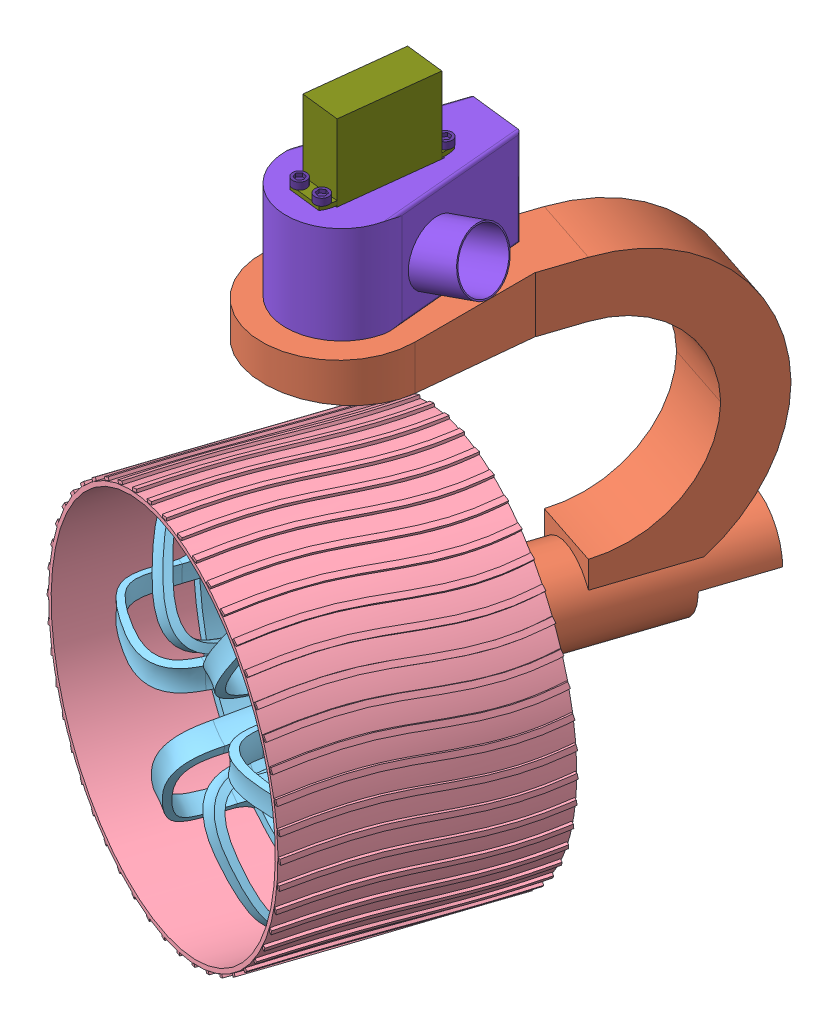
SolidWorks assembly Wheel + connector(left,front), configuration Default. Lengths in mm.
Overall size (198.17 269 202.4).
30 component instances, 17 part files, 57 mates.
Components (placement in the parent):
- Wheel motor-1: Wheel motor [Default] at (-224.1215 -139.499 45.6441) x (-0.84319 -0.459235 -0.279525) z (-0.314669 0 0.949202) size (25 25 73.38)
- Wheel connector(left,front)-1: Wheel connector(left,front) [Default] at (-218.767 -84.5922 -10.1338) x (0.314669 0 -0.949202) z (0.949202 0 0.314669) size (150.03 127 55.1)
- connector to wheel-1: connector to wheel [Default] at (-234.2078 -143.7607 83.0711) x (0.91831 0.253041 0.304428) z (0.314669 0 -0.949202) size (25 25 12.5)
- Wheel-1: Wheel [Default] at (-237.9838 -143.7607 94.4615) x (-0.819181 0.505167 -0.271566) z (-0.314669 0 0.949202) size (132 132 85)
  - Wheel Part-1-1: Wheel Part-1 [Default] at origin size (132 132 85)
  - Wheel Part-2-1: Wheel Part-2 [Default] at (0 0 -2) size (127 128.13 59.75)
- M3 nut-1: M3 nut [Default] at (-232.3491 -136.9885 71.8352) x (-0.667163 0.71132 -0.22117) z (-0.314669 0 0.949202) size (5 6.35 2.75)
- M3 nut-2: M3 nut [Default] at (-237.0959 -145.532 70.2615) x (-0.240187 0.967455 -0.079624) z (-0.314669 0 0.949202) size (5 6.35 2.75)
- M3 nut-3: M3 nut [Default] at (-224.2396 -141.9894 74.5235) x (-0.240187 0.967455 -0.079624) z (-0.314669 0 0.949202) size (5 6.35 2.75)
- M3 nut-4: M3 nut [Default] at (-228.9864 -150.5329 72.9499) x (0.251147 0.964362 0.083257) z (-0.314669 0 0.949202) size (5 6.35 2.75)
- M3 bolt for wheels-1: M3 bolt for wheels [Default] at (-244.176 -145.532 91.6186) x (-0.876804 -0.383049 -0.290668) z (0.314669 0 -0.949202) size (5 5 25.25)
- M3 bolt for wheels-2: M3 bolt for wheels [Default] at (-236.0665 -150.5329 94.3069) x (-0.876804 -0.383049 -0.290668) z (0.314669 0 -0.949202) size (5 5 25.25)
- M3 bolt for wheels-3: M3 bolt for wheels [Default] at (-231.3196 -141.9894 95.8806) x (-0.876804 -0.383049 -0.290668) z (0.314669 0 -0.949202) size (5 5 25.25)
- M3 bolt for wheels-4: M3 bolt for wheels [Default] at (-239.4291 -136.9885 93.1922) x (-0.876804 -0.383049 -0.290668) z (0.314669 0 -0.949202) size (5 5 25.25)
- Steering connector(left,front)-1: Steering connector(left,front) [Default] at (-237.0258 -27.059 85.0059) x (0.114579 0 -0.993414) z (0.993414 0 0.114579) size (70 36.07 55.83)
- Washer(M6)-1: Washer(M6) [Default] at (-237.0258 -27.559 85.0059) size (8.76 0.5 8.76)
- double row cylindrical roller bearing_is-1: double row cylindrical roller bearing_is [IS 6458 DC - 49-6-S] at (-237.0258 -22.059 85.0059) x (0.999846 0 -0.017538) z (0 -1 0) size (15 15 10)
- Steering thor joint-1: Steering thor joint [Default] at (-244.3838 -19.7982 116.189) x (0.664698 0 0.747112) z (0 1 0) size (14.13 14.13 58.56)
  - bolt head-1: bolt head [Default] at (-18.4031 26.2188 19.7392) size (14 14 8)
  - Bogie bolt-1: Bogie bolt [Default] at (-18.4064 26.2246 14.7392) x (-1 0 0) z (0 0 -1) size (9 10.39 55.56)
  - Bolt servo connector-1: Bolt servo connector [Default] at (-18.4031 26.2188 19.7392) x (0.99996 0.008969 0) z (0 0 1) size (14 14 3)
- Bogie nut-1: Bogie nut [Default] at (-237.0258 -41.6423 85.0059) x (0.979367 0 -0.20209) z (0.20209 0 0.979367) size (8.33 4.53 10.58)
- Bogie nut-2: Bogie nut [Default] at (-237.0258 -45.809 85.0059) x (0.949996 0 0.312263) z (-0.312263 0 0.949996) size (8.33 4.53 10.58)
- Servo Assembly-1: Servo Assembly [Default] at (-233.5333 1.941 85.2537) x (0.993414 0 0.114579) z (-0.114579 0 0.993414) size (14 34 44) (flexible)
  - servo shaft-1: servo shaft [Default] at (-3.4993 -1 0.1605) x (0.455252 0 0.890363) z (-0.890363 0 0.455252) size (5 18 5)
  - Servo motor-1: Servo motor [Default] at (-3.4993 3 -9.8395) size (14 30 44)
- M3 bolt-1: M3 bolt [Default] at (-242.6949 10.691 94.4349) x (0.160133 0 -0.987095) z (0 -1 0) size (5 5 12.17)
- M3 bolt-2: M3 bolt [Default] at (-229.0694 10.691 55.7212) x (-0.812704 0 -0.582677) z (0 -1 0) size (5 5 12.17)
- M3 bolt-3: M3 bolt [Default] at (-233.6548 10.691 95.4776) x (-0.635136 0 -0.772401) z (0 -1 0) size (5 5 12.17)
- M3 bolt-4: M3 bolt [Default] at (-238.1094 10.691 54.6785) x (-0.32715 0 -0.944972) z (0 -1 0) size (5 5 12.17)
Mates (geometry in assembly coordinates):
- Concentric9: concentric: cylinder of Wheel motor-1 through (-228.5514 -139.5591 59.1056) axis (0.314669 0 -0.949202) radius 12.5004; cylinder of Wheel connector(left,front)-1 through (-229.891 -139.559 63.1463) axis (0.314669 0 -0.949202) radius 12.5
- Concentric18: concentric: cylinder of Wheel motor-1 through (-234.2078 -143.7607 83.0711) axis (0.314669 0 -0.949202) radius 2.0271; cylinder of Wheel connector(left,front)-1 through (-196.7867 -143.7607 -29.8101) axis (-0.314669 0 0.949202) radius 2.435
- Concentric21: concentric: cylinder of Wheel motor-1 through (-234.2078 -143.7607 83.0711) axis (0.314669 0 -0.949202) radius 2.0271; cylinder of connector to wheel-1 through (-234.2081 -143.7607 83.072) axis (0.314669 0 -0.949202) radius 2.025
- Coincident1: coincident: axis of connector to wheel-1 through (-235.8891 -136.9885 82.5137) axis (0.314669 0 -0.949202); axis of M3 nut-1 through (-232.4874 -136.9885 72.2525) axis (-0.314669 0 0.949202)
- Coincident2: coincident: axis of connector to wheel-1 through (-240.6359 -145.532 80.9401) axis (0.314669 0 -0.949202); axis of M3 nut-2 through (-237.2343 -145.532 70.6789) axis (-0.314669 0 0.949202)
- Coincident3: coincident: axis of connector to wheel-1 through (-227.7796 -141.9894 85.202) axis (0.314669 0 -0.949202); axis of M3 nut-3 through (-224.3444 -141.9894 74.8398) axis (-0.314669 0 0.949202)
- Coincident4: coincident: axis of connector to wheel-1 through (-232.5265 -150.5329 83.6284) axis (0.314669 0 -0.949202); axis of M3 nut-4 through (-229.0913 -150.5329 73.2662) axis (-0.314669 0 0.949202)
- Coincident5: coincident: plane of connector to wheel-1 through (-231.0611 -143.7607 73.579) normal (0.314669 0 -0.949202); plane of M3 nut-1 through (-232.7424 -136.9885 73.0217) normal (-0.314669 0 0.949202)
- Parallel1: parallel: plane of connector to wheel-1 through (-233.4376 -141.2269 72.7912) normal (-0.667163 0.71132 -0.22117); plane of M3 nut-1 through (-232.049 -139.7813 73.2515) normal (0.667163 -0.71132 0.22117)
- Parallel2: parallel: plane of connector to wheel-1 through (-231.6616 -141.3421 73.38) normal (0.240187 -0.967455 0.079624); plane of M3 nut-2 through (-236.7643 -142.7481 71.6884) normal (-0.240187 0.967455 -0.079624)
- Coincident7: coincident: plane of connector to wheel-1 through (-231.0611 -143.7607 73.579) normal (0.314669 0 -0.949202); plane of M3 nut-2 through (-237.4893 -145.532 71.448) normal (-0.314669 0 0.949202)
- Coincident8: coincident: plane of connector to wheel-1 through (-228.6845 -146.2946 74.3669) normal (0.667163 -0.71132 0.22117); plane of M3 nut-4 through (-230.0731 -147.7401 73.9066) normal (-0.667163 0.71132 -0.22117)
- Coincident9: coincident: plane of connector to wheel-1 through (-231.0611 -143.7607 73.579) normal (0.314669 0 -0.949202); plane of M3 nut-4 through (-229.3798 -150.5329 74.1364) normal (-0.314669 0 0.949202)
- Parallel3: parallel: plane of connector to wheel-1 through (-225.28 -137.7426 75.4955) normal (-0.675186 -0.702868 -0.22383); plane of M3 nut-3 through (-227.2838 -142.7199 74.8312) normal (-0.675186 -0.702868 -0.22383)
- Coincident10: coincident: plane of connector to wheel-1 through (-231.0611 -143.7607 73.579) normal (0.314669 0 -0.949202); plane of M3 nut-3 through (-224.6329 -141.9894 75.71) normal (-0.314669 0 0.949202)
- Coincident11: coincident: axis of Wheel motor-1 through (-234.1652 -143.7607 82.9428) axis (0.314669 0 -0.949202); axis of Wheel-1/Wheel Part-1-1 through (-251.3572 -143.7607 134.8025) axis (0.314669 0 -0.949202)
- Coincident13: coincident: plane of connector to wheel-1 through (-234.2078 -143.7607 83.0711) normal (-0.314669 0 0.949202); plane of Wheel-1/Wheel Part-2-1 through (-234.2078 -143.7607 83.0711) normal (0.314669 0 -0.949202)
- Concentric22: concentric: cylinder of connector to wheel-1 through (-232.5268 -150.5329 83.6294) axis (0.314669 0 -0.949202) radius 1.71; cylinder of Wheel-1/Wheel Part-2-1 through (-247.7891 -150.5329 129.6685) axis (0.314669 0 -0.949202) radius 1.71
- Coincident14: coincident: axis of Wheel-1/Wheel Part-2-1 through (-243.7826 -145.532 90.4321) axis (0.314669 0 -0.949202); axis of M3 bolt for wheels-1 through (-236.7026 -145.532 69.075) axis (-0.314669 0 0.949202)
- Coincident15: coincident: plane of Wheel-1/Wheel Part-2-1 through (-243.7826 -145.532 90.4321) normal (-0.314669 0 0.949202); plane of M3 bolt for wheels-1 through (-243.7826 -145.532 90.4321) normal (0.314669 0 -0.949202)
- Coincident16: coincident: axis of Wheel-1/Wheel Part-2-1 through (-235.6731 -150.5329 93.1204) axis (0.314669 0 -0.949202); axis of M3 bolt for wheels-2 through (-228.5931 -150.5329 71.7634) axis (-0.314669 0 0.949202)
- Coincident17: coincident: plane of Wheel-1/Wheel Part-2-1 through (-237.3545 -143.7607 92.5631) normal (-0.314669 0 0.949202); plane of M3 bolt for wheels-2 through (-235.6731 -150.5329 93.1204) normal (0.314669 0 -0.949202)
- Coincident18: coincident: axis of Wheel-1/Wheel Part-2-1 through (-239.0358 -136.9885 92.0057) axis (0.314669 0 -0.949202); axis of M3 bolt for wheels-4 through (-231.9557 -136.9885 70.6487) axis (-0.314669 0 0.949202)
- Coincident19: coincident: plane of Wheel-1/Wheel Part-2-1 through (-239.0358 -136.9885 92.0057) normal (-0.314669 0 0.949202); plane of M3 bolt for wheels-4 through (-239.0358 -136.9885 92.0057) normal (0.314669 0 -0.949202)
- Coincident20: coincident: axis of Wheel-1/Wheel Part-2-1 through (-230.9263 -141.9894 94.6941) axis (0.314669 0 -0.949202); axis of M3 bolt for wheels-3 through (-223.8462 -141.9894 73.337) axis (-0.314669 0 0.949202)
- Coincident21: coincident: plane of Wheel-1/Wheel Part-2-1 through (-230.9263 -141.9894 94.6941) normal (-0.314669 0 0.949202); plane of M3 bolt for wheels-3 through (-230.9263 -141.9894 94.6941) normal (0.314669 0 -0.949202)
- Coincident22: coincident: plane of Wheel motor-1 through (-236.2696 -139.5591 82.3876) normal (-0.314669 0 0.949202); plane of connector to wheel-1 through (-234.2078 -143.7607 83.0711) normal (-0.314669 0 0.949202)
- Concentric23: concentric: cylinder of Wheel connector(left,front)-1 through (-237.0258 -51.559 85.0059) axis (0 1 0) radius 3; circle of Steering connector(left,front)-1
- Concentric24: concentric: cylinder of Steering connector(left,front)-1 through (-237.0258 -17.059 85.0059) axis (0 -1 0) radius 7.5; cylinder of double row cylindrical roller bearing_is-1 through (-237.0258 -72.4506 85.0059) axis (0 -1 0) radius 7.5
- Coincident23: coincident: plane of Steering connector(left,front)-1 through (-237.0258 -17.059 85.0059) normal (0 -1 0); plane of double row cylindrical roller bearing_is-1 through (-236.8943 -17.059 92.5047) normal (0 1 0)
- Coincident24: coincident: plane of Washer(M6)-1 through (-237.0258 -27.059 85.0059) normal (0 1 0); plane of double row cylindrical roller bearing_is-1 through (-236.9732 -27.059 88.0054) normal (0 -1 0)
- Concentric25: concentric: cylinder of Washer(M6)-1 through (-237.0258 -27.059 85.0059) axis (0 -1 0) radius 3; cylinder of double row cylindrical roller bearing_is-1 through (-237.0258 -92.9216 85.0059) axis (0 -1 0) radius 3
- Coincident25: coincident: plane of Wheel connector(left,front)-1 through (-195.0369 -27.559 -2.2671) normal (0 1 0); plane of Washer(M6)-1 through (-237.0258 -27.559 85.0059) normal (0 -1 0)
- Coincident32: coincident: plane of Steering connector(left,front)-1 through (-237.0258 -7.059 85.0059) normal (0 1 0); plane of Steering thor joint-1/bolt head-1 through (-237.0279 -7.059 85.0122) normal (0 -1 0)
- Concentric26: concentric: cylinder of Steering connector(left,front)-1 through (-237.0258 8.4751 85.0059) axis (0 -1 0) radius 3; cylinder of Steering thor joint-1/Bogie bolt-1 through (-237.0258 -55.309 85.0059) axis (0 1 0) radius 2.5
- Coincident33: coincident: plane of Wheel motor-1 through (-229.8909 -139.5591 63.1463) normal (-0.314669 0 0.949202); plane of Wheel connector(left,front)-1 through (-241.756 -84.5922 59.2129) normal (0.314669 0 -0.949202)
- Coincident83: coincident: axis of Steering thor joint-1/Bogie bolt-1 through (-237.0258 -55.309 85.0059) axis (0 1 0); axis of Bogie nut-1 through (-237.0258 -39.559 85.0059) axis (0 -1 0)
- Parallel27: parallel: plane of Wheel connector(left,front)-1 through (-236.0535 -49.559 89.7179) normal (-0.664698 0 -0.747112); plane of Bogie nut-1 through (-236.0535 -39.559 89.7179) normal (0.664698 0 0.747112)
- Coincident85: coincident: plane of Wheel connector(left,front)-1 through (-218.767 -39.559 -10.1338) normal (0 -1 0); plane of Bogie nut-1 through (-237.0258 -39.559 85.0059) normal (0 1 0)
- Coincident86: coincident: plane of Bogie nut-1 through (-237.0258 -43.7257 85.0059) normal (0 -1 0); plane of Bogie nut-2 through (-237.0258 -43.7257 85.0059) normal (0 1 0)
- Parallel29: parallel: plane of Steering thor joint-1/Bogie bolt-1 through (-240.9079 -0.059 88.4597) normal (-0.979367 0 0.20209); plane of Bogie nut-1 through (-241.5927 -39.559 83.4919) normal (-0.979367 0 0.20209)
- Lock3: lock: unknown of Bogie nut-1; unknown of Bogie nut-2
- Coincident84: coincident: axis of Steering thor joint-1/Bogie bolt-1 through (-237.0258 -55.309 85.0059) axis (0 1 0); axis of Bogie nut-2 through (-237.0258 -43.7257 85.0059) axis (0 -1 0)
- Concentric20: concentric: cylinder of Steering thor joint-1/Bolt servo connector-1 through (-237.0279 2.941 85.0122) axis (0 -1 0) radius 2.5; cylinder of Servo Assembly-1/servo shaft-1 through (-237.0279 18.941 85.0122) axis (0 -1 0) radius 2.5
- Parallel26: parallel: plane of Steering connector(left,front)-1 through (-245.3358 -7.059 91.5971) normal (0.993414 0 0.114579); plane of Servo Assembly-1/Servo motor-1 through (-242.836 34.941 74.276) normal (-0.993414 0 -0.114579)
- LimitAngle1: limit planar angle = 0.205276 rad: plane of Steering connector(left,front)-1 through (-241.231 7.941 34.1894) normal (0.114579 0 -0.993414); plane of Wheel connector(left,front)-1 through (-199.9974 -139.559 -27.0279) normal (0.314669 0 -0.949202)
- Parallel31: parallel: plane of Steering connector(left,front)-1 through (-230.4346 -7.059 93.3158) normal (-0.993414 0 -0.114579); plane of Servo Assembly-1/Servo motor-1 through (-228.9282 34.941 75.8801) normal (0.993414 0 0.114579)
- Coincident88: coincident: plane of Steering connector(left,front)-1 through (-237.0258 7.941 85.0059) normal (0 1 0); plane of Servo Assembly-1/Servo motor-1 through (-235.8821 7.941 75.0781) normal (0 -1 0)
- Coincident89: coincident: plane of Steering thor joint-1/Bolt servo connector-1 through (-237.0279 0.941 85.0122) normal (0 1 0); plane of Servo Assembly-1/servo shaft-1 through (-237.0279 0.941 85.0122) normal (0 -1 0)
- Concentric27: concentric: cylinder of Servo Assembly-1/Servo motor-1 through (-242.6949 9.441 94.4349) axis (0 -1 0) radius 1.5; cylinder of M3 bolt-1 through (-242.6949 9.441 94.4349) axis (0 1 0) radius 2.5
- Coincident90: coincident: plane of Servo Assembly-1/Servo motor-1 through (-235.8821 9.441 75.0781) normal (0 1 0); plane of M3 bolt-1 through (-242.6949 9.441 94.4349) normal (0 -1 0)
- Concentric30: concentric: cylinder of Servo Assembly-1/Servo motor-1 through (-233.6548 9.441 95.4776) axis (0 -1 0) radius 1.5; cylinder of M3 bolt-3 through (-233.6548 9.441 95.4776) axis (0 1 0) radius 2.5
- Coincident91: coincident: plane of Servo Assembly-1/Servo motor-1 through (-235.8821 9.441 75.0781) normal (0 1 0); plane of M3 bolt-3 through (-233.6548 9.441 95.4776) normal (0 -1 0)
- Concentric31: concentric: cylinder of Servo Assembly-1/Servo motor-1 through (-238.1094 9.441 54.6785) axis (0 -1 0) radius 1.5; cylinder of M3 bolt-4 through (-238.1094 9.441 54.6785) axis (0 1 0) radius 2.5
- Concentric32: concentric: cylinder of Servo Assembly-1/Servo motor-1 through (-229.0694 9.441 55.7212) axis (0 -1 0) radius 1.5; cylinder of M3 bolt-2 through (-229.0694 9.441 55.7212) axis (0 1 0) radius 2.5
- Coincident92: coincident: plane of Servo Assembly-1/Servo motor-1 through (-235.8821 9.441 75.0781) normal (0 1 0); plane of M3 bolt-2 through (-229.0694 9.441 55.7212) normal (0 -1 0)
- Coincident93: coincident: plane of Servo Assembly-1/Servo motor-1 through (-235.8821 9.441 75.0781) normal (0 1 0); plane of M3 bolt-4 through (-238.1094 9.441 54.6785) normal (0 -1 0)
